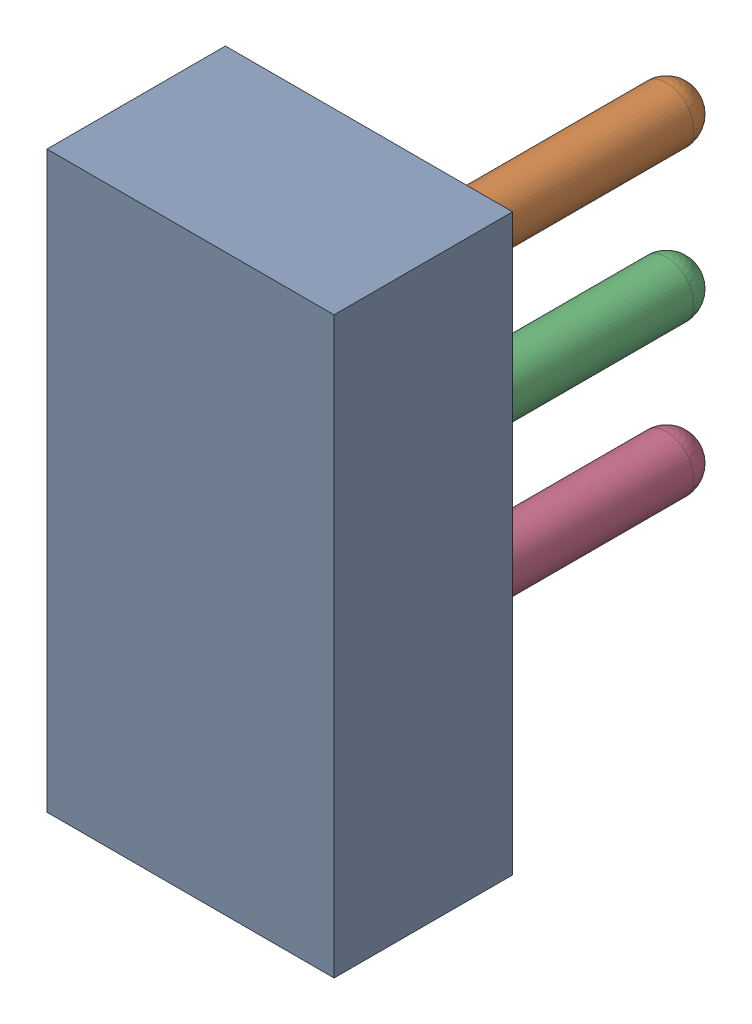
SolidWorks assembly RV1, configuration Défaut. Lengths in mm.
Overall size (4.83 9.65 8.46).
5 component instances, 4 part files, 0 mates.
Components (placement in the parent):
- Open CASCADE STEP translator 6.8 1.9.1-1: Open CASCADE STEP translator 6.8 1.9.1 [Défaut] at origin size (4.83 9.65 8.46)
  - Body_1_6-1: Body_1_6 [Défaut] at origin size (4.83 9.65 3)
  - Pin_1_3-1: Pin_1_3 [Défaut] x (0 -1 0) z (0 0 1) size (0.92 0.92 7.42)
  - Pin_2_3-1: Pin_2_3 [Défaut] at (2.54 -2.54 0) x (0 -1 0) z (0 0 1) size (0.92 0.92 7.42)
  - Pin_3_2-1: Pin_3_2 [Défaut] at (5.08 -5.08 0) x (0 -1 0) z (0 0 1) size (0.92 0.92 7.42)
